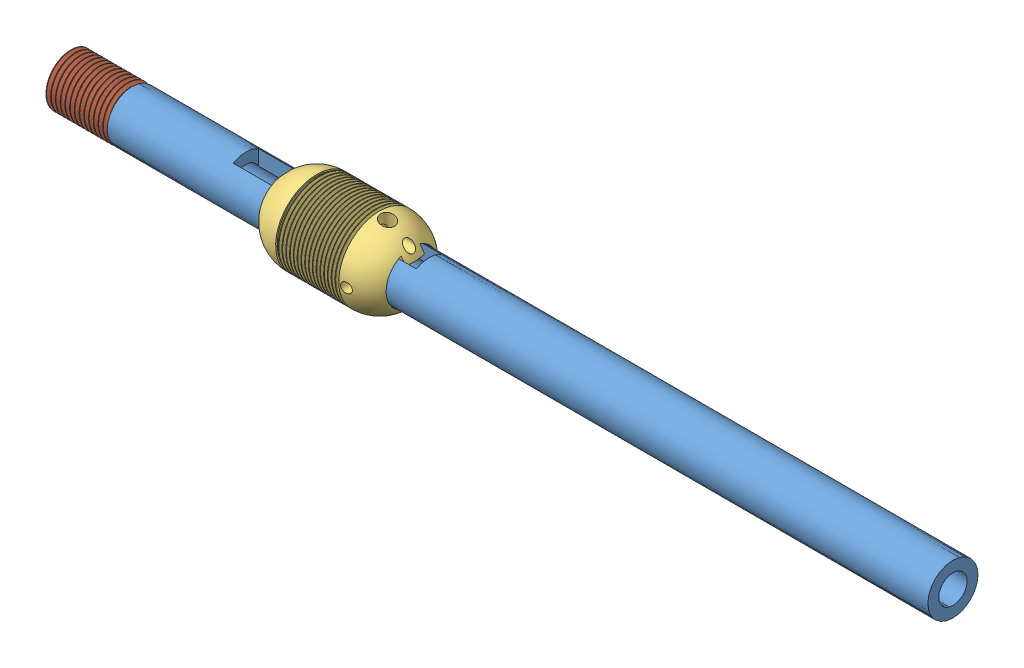
SolidWorks assembly slider assembly v-5 22-Nov-2017, configuration Default. Lengths in mm.
Overall size (140.35 17.1 13.86).
3 component instances, 3 part files, 3 mates.
Components (placement in the parent):
- wheel_handle_body_slider v-4 06-Nov-2017-1: wheel_handle_body_slider v-4 06-Nov-2017 [Default] at (-10.0168 48.9172 77.5775) size (130 7.94 7.94)
- M8X0.75-1: M8X0.75 [91290A414] at (-10.0168 48.9172 77.5775) x (0 0 -1) z (1 0 0) size (13 13 10.51)
- slider v-6 22-Nov-2017-1: slider v-6 22-Nov-2017 [Default] at (29.2031 48.9172 77.5775) x (0 0.053623 -0.998561) z (1 0 0) size (13 16.42 21.82)
Mates (geometry in assembly coordinates):
- Coincident1: coincident anti-aligned: plane of wheel_handle_body_slider v-4 06-Nov-2017-1 through (-10.0168 48.9172 77.5775) normal (-1 0 0); plane of M8X0.75-1 through (-10.0168 48.9172 77.5775) normal (1 0 0)
- Concentric1: concentric anti-aligned: circle of wheel_handle_body_slider v-4 06-Nov-2017-1; circle of M8X0.75-1
- Concentric2: concentric aligned: circle of wheel_handle_body_slider v-4 06-Nov-2017-1; circle of slider v-6 22-Nov-2017-1
